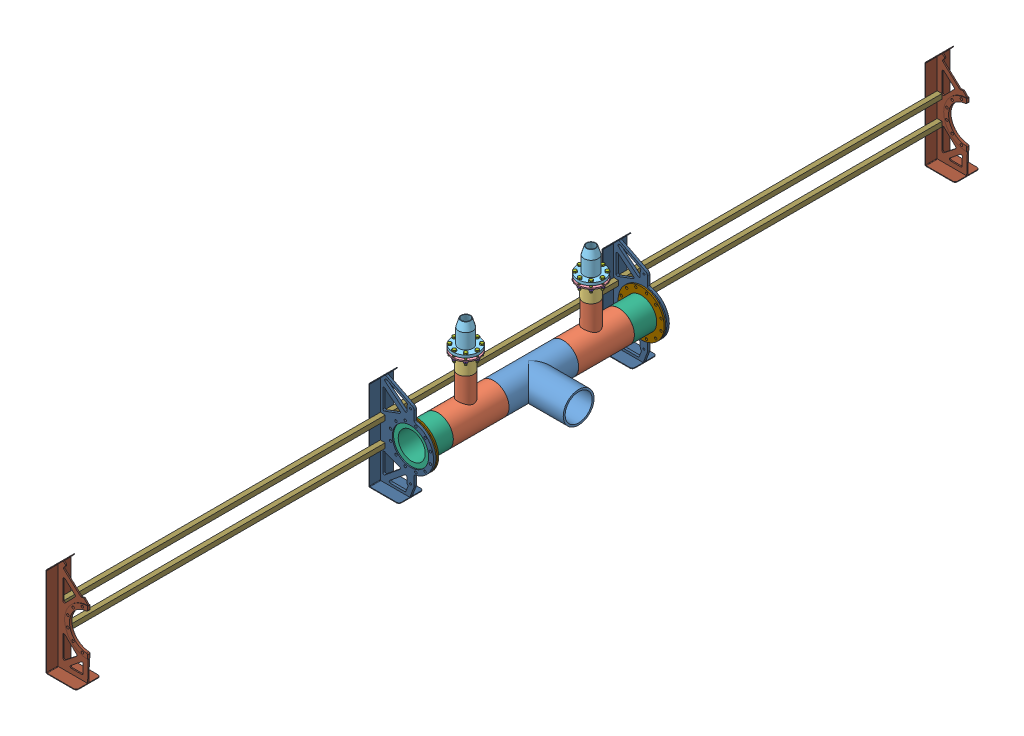
SolidWorks assembly Animation Assembly - Copie, configuration Default. Lengths in mm.
Overall size (2322.65 15000 15000).
51 component instances, 12 part files, 27 mates.
Components (placement in the parent):
- 12_NOM_Tee_Branch-1: 12_NOM_Tee_Branch [Default] at origin size (688.98 323.85 730.25)
- 12_to_6_Tee_Reducer-1: 12_to_6_Tee_Reducer [Default] at (0 0 657.225) x (0 0 -1) z (1 0 0) size (584.2 568.32 323.85)
- 6_NOM_Flange_Adapter-1: 6_NOM_Flange_Adapter [Default] at (0 609.6 657.225) x (0 -1 0) z (-0.546944 0 0.837169) size (203.2 215.9 215.9)
- 6_NOM_Class_150_Slip-On_Plate_Flange-1: 6_NOM_Class_150_Slip-On_Plate_Flange [Default] at (0 576.58 657.225) x (1 0 0) z (0 1 0) size (279.4 279.4 12.7)
- Nozzle(Flanged)-1: Nozzle(Flanged) [Default] at (0 876.3 657.225) x (0 -1 0) z (-0.382683 0 0.92388) size (266.7 275.84 275.84)
- 12_NOM_Flange_Adapter-1: 12_NOM_Flange_Adapter [Default] at (0 0 1223.645) size (381 381 274.32)
- hex bolt_ai-2: hex bolt_ai [HBOLT 0.8750-9x4x2-S] at (0 652.6316 777.875) x (0 -1 0) z (-0.973486 0 0.228748) size (116.94 38.48 33.32)
- hex nut_ai-2: hex nut_ai [HNUT 0.8750-14-B-C] at (0 556.8696 777.875) x (1 0 0) z (0 -1 0) size (33.32 38.48 19.71)
- hex bolt_ai-3: hex bolt_ai [HBOLT 0.8750-9x4x2-S] at (85.3124 652.6316 742.5374) x (0 -1 0) z (-0.526609 0 0.850108) size (116.94 38.48 33.32)
- hex bolt_ai-4: hex bolt_ai [HBOLT 0.8750-9x4x2-S] at (120.65 652.6316 657.225) x (0 -1 0) z (0.228748 0 0.973486) size (116.94 38.48 33.32)
- hex bolt_ai-5: hex bolt_ai [HBOLT 0.8750-9x4x2-S] at (85.3124 652.6316 571.9126) x (0 -1 0) z (0.850108 0 0.526609) size (116.94 38.48 33.32)
- hex bolt_ai-6: hex bolt_ai [HBOLT 0.8750-9x4x2-S] at (0 652.6316 536.575) x (0 -1 0) z (0.973486 0 -0.228748) size (116.94 38.48 33.32)
- hex bolt_ai-7: hex bolt_ai [HBOLT 0.8750-9x4x2-S] at (-85.3124 652.6316 571.9126) x (0 -1 0) z (0.526609 0 -0.850108) size (116.94 38.48 33.32)
- hex bolt_ai-8: hex bolt_ai [HBOLT 0.8750-9x4x2-S] at (-120.65 652.6316 657.225) x (0 -1 0) z (-0.228748 0 -0.973486) size (116.94 38.48 33.32)
- hex bolt_ai-9: hex bolt_ai [HBOLT 0.8750-9x4x2-S] at (-85.3124 652.6316 742.5374) x (0 -1 0) z (-0.850108 0 -0.526609) size (116.94 38.48 33.32)
- hex nut_ai-3: hex nut_ai [HNUT 0.8750-14-B-C] at (85.3124 556.8696 742.5374) x (0.707107 0 -0.707107) z (0 -1 0) size (33.32 38.48 19.71)
- hex nut_ai-4: hex nut_ai [HNUT 0.8750-14-B-C] at (120.65 556.8696 657.225) x (0 0 -1) z (0 -1 0) size (33.32 38.48 19.71)
- hex nut_ai-5: hex nut_ai [HNUT 0.8750-14-B-C] at (85.3124 556.8696 571.9126) x (-0.707107 0 -0.707107) z (0 -1 0) size (33.32 38.48 19.71)
- hex nut_ai-6: hex nut_ai [HNUT 0.8750-14-B-C] at (0 556.8696 536.575) x (-1 0 0) z (0 -1 0) size (33.32 38.48 19.71)
- hex nut_ai-7: hex nut_ai [HNUT 0.8750-14-B-C] at (-85.3124 556.8696 571.9126) x (-0.707107 0 0.707107) z (0 -1 0) size (33.32 38.48 19.71)
- hex nut_ai-8: hex nut_ai [HNUT 0.8750-14-B-C] at (-120.65 556.8696 657.225) x (0 0 1) z (0 -1 0) size (33.32 38.48 19.71)
- hex nut_ai-9: hex nut_ai [HNUT 0.8750-14-B-C] at (-85.3124 556.8696 742.5374) x (0.707107 0 0.707107) z (0 -1 0) size (33.32 38.48 19.71)
- Class_150_Slip-On_Plate_Flange-1: Class_150_Slip-On_Plate_Flange [Default] at (0 0 1190.3075) x (0.965926 0.258819 0) z (0 0 1) size (482.6 482.6 15.88)
- Support_2-1: Support_2 [Default] at (-316.3 0 1223.645) x (0 0 1) z (0 1 0) size (254 563.95 994.12)
- Support_8-1: Support_8 [Default] at (-316.3 0 4609.465) x (0 0 1) z (0 1 0) size (254 322.65 994.12)
- Support_8-2: Support_8 [Default] at (-316.3 0 -4609.465) x (0 0 1) z (0 1 0) size (254 322.65 994.12)
- hex bolt_ai-78: hex bolt_ai [HBOLT 0.8750-9x4x2-S] at (120.65 652.6316 -657.225) x (0 -1 0) z (-0.228748 0 0.973486) size (116.94 38.48 33.32)
- 12_NOM_Flange_Adapter-5: 12_NOM_Flange_Adapter [Default] at (0 0 -1223.645) x (-1 0 0) z (0 0 -1) size (381 381 274.32)
- 12_to_6_Tee_Reducer-6: 12_to_6_Tee_Reducer [Default] at (0 0 -657.225) x (0 0 1) z (-1 0 0) size (584.2 568.32 323.85)
- hex nut_ai-112: hex nut_ai [HNUT 0.8750-14-B-C] at (-85.3124 556.8696 -742.5374) x (-0.707107 0 0.707107) z (0 -1 0) size (33.32 38.48 19.71)
- hex nut_ai-113: hex nut_ai [HNUT 0.8750-14-B-C] at (-85.3124 556.8696 -571.9126) x (0.707107 0 0.707107) z (0 -1 0) size (33.32 38.48 19.71)
- hex bolt_ai-114: hex bolt_ai [HBOLT 0.8750-9x4x2-S] at (-85.3124 652.6316 -571.9126) x (0 -1 0) z (-0.526609 0 -0.850108) size (116.94 38.48 33.32)
- hex nut_ai-114: hex nut_ai [HNUT 0.8750-14-B-C] at (-120.65 556.8696 -657.225) x (0 0 1) z (0 -1 0) size (33.32 38.48 19.71)
- hex nut_ai-115: hex nut_ai [HNUT 0.8750-14-B-C] at (0 556.8696 -536.575) x (1 0 0) z (0 -1 0) size (33.32 38.48 19.71)
- hex nut_ai-116: hex nut_ai [HNUT 0.8750-14-B-C] at (85.3124 556.8696 -571.9126) x (0.707107 0 -0.707107) z (0 -1 0) size (33.32 38.48 19.71)
- hex bolt_ai-115: hex bolt_ai [HBOLT 0.8750-9x4x2-S] at (0 652.6316 -536.575) x (0 -1 0) z (-0.973486 0 -0.228748) size (116.94 38.48 33.32)
- hex nut_ai-118: hex nut_ai [HNUT 0.8750-14-B-C] at (120.65 556.8696 -657.225) x (0 0 -1) z (0 -1 0) size (33.32 38.48 19.71)
- hex bolt_ai-116: hex bolt_ai [HBOLT 0.8750-9x4x2-S] at (85.3124 652.6316 -571.9126) x (0 -1 0) z (-0.850108 0 0.526609) size (116.94 38.48 33.32)
- hex nut_ai-119: hex nut_ai [HNUT 0.8750-14-B-C] at (85.3124 556.8696 -742.5374) x (-0.707107 0 -0.707107) z (0 -1 0) size (33.32 38.48 19.71)
- hex bolt_ai-117: hex bolt_ai [HBOLT 0.8750-9x4x2-S] at (-120.65 652.6316 -657.225) x (0 -1 0) z (0.228748 0 -0.973486) size (116.94 38.48 33.32)
- hex bolt_ai-118: hex bolt_ai [HBOLT 0.8750-9x4x2-S] at (-85.3124 652.6316 -742.5374) x (0 -1 0) z (0.850108 0 -0.526609) size (116.94 38.48 33.32)
- hex nut_ai-120: hex nut_ai [HNUT 0.8750-14-B-C] at (0 556.8696 -777.875) x (-1 0 0) z (0 -1 0) size (33.32 38.48 19.71)
- Support_2-2: Support_2 [Default] at (-316.3 0 -1223.645) x (0 0 1) z (0 1 0) size (254 563.95 994.12)
- hex bolt_ai-119: hex bolt_ai [HBOLT 0.8750-9x4x2-S] at (0 652.6316 -777.875) x (0 -1 0) z (0.973486 0 0.228748) size (116.94 38.48 33.32)
- Class_150_Slip-On_Plate_Flange-6: Class_150_Slip-On_Plate_Flange [Default] at (0 0 -1190.3075) x (0.965926 0.258819 0) z (0 0 1) size (482.6 482.6 15.88)
- 6_NOM_Class_150_Slip-On_Plate_Flange-9: 6_NOM_Class_150_Slip-On_Plate_Flange [Default] at (0 576.58 -657.225) x (1 0 0) z (0 1 0) size (279.4 279.4 12.7)
- 6_NOM_Flange_Adapter-9: 6_NOM_Flange_Adapter [Default] at (0 609.6 -657.225) x (0 -1 0) z (0.546944 0 0.837169) size (203.2 215.9 215.9)
- Nozzle(Flanged)-9: Nozzle(Flanged) [Default] at (0 876.3 -657.225) x (0 -1 0) z (0.382683 0 0.92388) size (266.7 275.84 275.84)
- hex bolt_ai-121: hex bolt_ai [HBOLT 0.8750-9x4x2-S] at (85.3124 652.6316 -742.5374) x (0 -1 0) z (0.526609 0 0.850108) size (116.94 38.48 33.32)
- crossmember-1: crossmember [Défaut<As Machined>] at (-290.9 125.8132 4603.115) x (0 0 -1) z (-1 0 0) size (9206.23 50.8 50.8)
- crossmember-2: crossmember [Défaut<As Machined>] at (-290.9 -125.8132 4603.115) x (0 0 -1) z (1 0 0) size (9206.23 50.8 50.8)
Mates (geometry in assembly coordinates):
- Coincident1: coordinate: unknown of 12_NOM_Tee_Branch-1
- Concentric1: concentric anti-aligned: cylinder of 12_NOM_Tee_Branch-1 through (0 0 365.125) axis (0 0 -1) radius 141.732; cylinder of 12_to_6_Tee_Reducer-1 through (0 0 657.225) axis (0 0 1) radius 141.732
- Parallel3: parallel aligned: plane of 12_to_6_Tee_Reducer-1 through (0 406.4 657.225) normal (0 1 0)
- Coincident3: coincident anti-aligned: plane of 12_NOM_Tee_Branch-1 through (0 0 365.125) normal (0 0 1); plane of 12_to_6_Tee_Reducer-1 through (0 161.925 365.125) normal (0 0 -1)
- Concentric4: concentric aligned: cylinder of 12_to_6_Tee_Reducer-1 through (0 -208.306 657.225) axis (0 1 0) radius 73.6473; cylinder of 6_NOM_Flange_Adapter-1 through (0 609.6 657.225) axis (0 1 0) radius 73.6473
- Coincident6: coincident anti-aligned: plane of 12_to_6_Tee_Reducer-1 through (0 406.4 657.225) normal (0 1 0); plane of 6_NOM_Flange_Adapter-1 through (61.6552 406.4 697.506) normal (0 -1 0)
- Concentric5: concentric anti-aligned: cylinder of 6_NOM_Flange_Adapter-1 through (0 609.6 657.225) axis (0 1 0) radius 84.1375; cylinder of 6_NOM_Class_150_Slip-On_Plate_Flange-1 through (0 589.28 657.225) axis (0 -1 0) radius 84.1375
- Coincident7: coincident anti-aligned: plane of 6_NOM_Flange_Adapter-1 through (70.4373 589.28 703.2435) normal (0 -1 0); plane of 6_NOM_Class_150_Slip-On_Plate_Flange-1 through (0 589.28 657.225) normal (0 1 0)
- Concentric6: concentric aligned: cylinder of 6_NOM_Flange_Adapter-1 through (0 609.6 657.225) axis (0 1 0) radius 73.6473; cylinder of Nozzle(Flanged)-1 through (0 876.3 657.225) axis (0 1 0) radius 68.795
- Coincident8: coincident anti-aligned: plane of 6_NOM_Flange_Adapter-1 through (90.3724 609.6 716.2676) normal (0 1 0); plane of Nozzle(Flanged)-1 through (0 609.6 657.225) normal (0 -1 0)
- Concentric7: concentric anti-aligned: cylinder of 6_NOM_Class_150_Slip-On_Plate_Flange-1 through (120.65 589.28 657.225) axis (0 1 0) radius 11.176; cylinder of Nozzle(Flanged)-1 through (120.65 609.6 657.225) axis (0 -1 0) radius 11.176
- Concentric8: concentric aligned: cylinder of 12_to_6_Tee_Reducer-1 through (0 0 657.225) axis (0 0 1) radius 141.732; cylinder of 12_NOM_Flange_Adapter-1 through (0 0 1223.645) axis (0 0 1) radius 141.732
- Coincident9: coincident anti-aligned: plane of 12_to_6_Tee_Reducer-1 through (0 161.925 949.325) normal (0 0 1); plane of 12_NOM_Flange_Adapter-1 through (0 141.732 949.325) normal (0 0 -1)
- Concentric10: concentric anti-aligned: cylinder of Nozzle(Flanged)-1 through (0 609.6 777.875) axis (0 -1 0) radius 11.176; cylinder of hex bolt_ai-2 through (0 652.6316 777.875) axis (0 1 0) radius 11.1125
- Coincident11: coincident anti-aligned: plane of Nozzle(Flanged)-1 through (0 637.29 657.225) normal (0 1 0); plane of hex bolt_ai-2 through (4.4011 637.29 796.6049) normal (0 -1 0)
- Concentric11: concentric anti-aligned: circle of hex bolt_ai-2; cylinder of hex nut_ai-2 through (0 576.58 777.875) axis (0 -1 0) radius 10.3187
- Coincident12: coincident anti-aligned: plane of 6_NOM_Class_150_Slip-On_Plate_Flange-1 through (0 576.58 657.225) normal (0 -1 0); plane of hex nut_ai-2 through (-33.3248 576.58 777.875) normal (0 1 0)
- Concentric12: concentric anti-aligned: cylinder of 12_NOM_Flange_Adapter-1 through (0 0 1223.645) axis (0 0 1) radius 161.925; cylinder of Class_150_Slip-On_Plate_Flange-1 through (0 0 1198.245) axis (0 0 -1) radius 163.576
- Coincident13: coincident anti-aligned: plane of 12_NOM_Flange_Adapter-1 through (0 161.925 1198.245) normal (0 0 -1); plane of Class_150_Slip-On_Plate_Flange-1 through (0 0 1198.245) normal (0 0 1)
- Concentric13: concentric aligned: cylinder of 12_NOM_Flange_Adapter-1 through (0 0 1223.645) axis (0 0 1) radius 190.5; cylinder of Support_2-1 through (0 0 1210.945) axis (0 0 1) radius 190.5
- Parallel5: parallel anti-aligned: plane of Support_2-1 through (-322.65 0 1223.645) normal (-1 0 0)
- Distance1: distance = 12.7 mm anti-aligned: plane of Support_2-1 through (-316.3 0 1210.945) normal (0 0 -1); plane of Class_150_Slip-On_Plate_Flange-1 through (0 0 1198.245) normal (0 0 1)
- Concentric14: concentric aligned: cylinder of Class_150_Slip-On_Plate_Flange-1 through (152.6644 152.6644 1198.245) axis (0 0 1) radius 12.7; cylinder of Support_2-1 through (152.6644 152.6644 1210.945) axis (0 0 1) radius 12.7
- Parallel6: parallel anti-aligned: plane of Support_8-1 through (-322.65 0 4609.465) normal (-1 0 0)
- Coincident27: coincident anti-aligned: plane of Support_2-2 through (-316.3 100.4132 -1236.345) normal (0 1 0); plane of crossmember-1 through (-316.3 100.4132 -4603.115) normal (0 -1 0)
- Coincident29: coincident anti-aligned: plane of Support_2-2 through (-265.5 0 -1236.345) normal (-1 0 0); plane of crossmember-1 through (-265.5 151.2132 -4603.115) normal (1 0 0)
- Coincident32: coincident anti-aligned: plane of Support_8-1 through (-316.3 0 4603.115) normal (0 0 -1); plane of crossmember-1 through (-290.9 125.8132 4603.115) normal (0 0 1)
